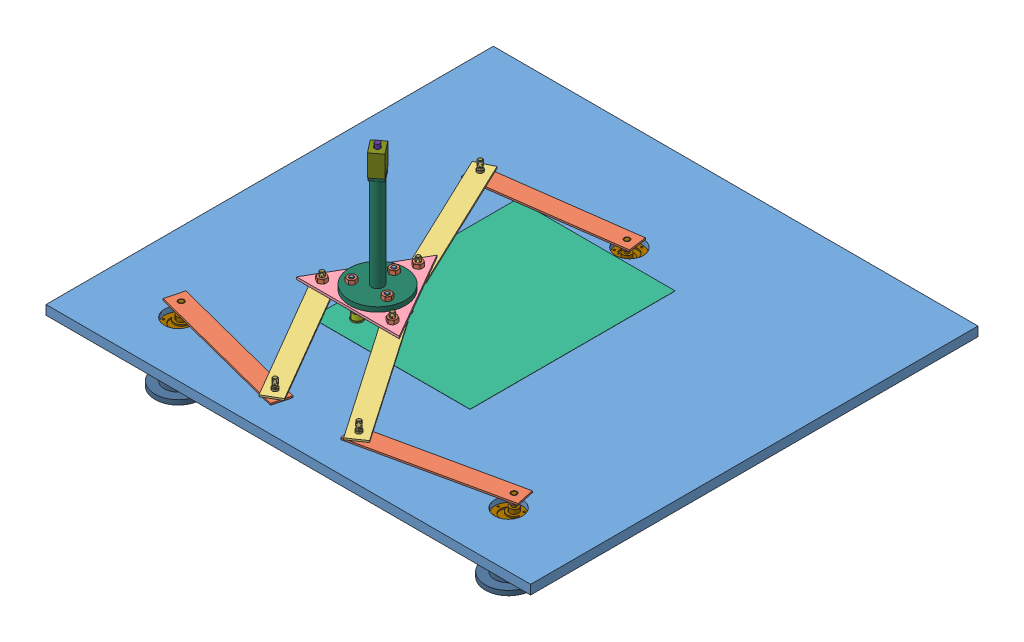
SolidWorks assembly 10_Full_3R_Assembly_rev2, configuration Default. Lengths in mm.
Overall size (660.4 280.02 609.6).
57 component instances, 20 part files, 127 mates.
Components (placement in the parent):
- 01_Base_Plate-1: 01_Base_Plate [Default] at (-311.7855 -6.35 287.7555) size (660.4 12.7 609.6)
- 02_A_Link-1: 02_A_Link [Default] at (-224.6047 18.389 215.2577) x (0.96847 0 0.24913) z (-0.24913 0 0.96847) size (203.2 2.29 25.4)
- 03_B_Link-1: 03_B_Link [Default] at (-19.5777 22.6594 254.9869) x (-0.503939 0 -0.863739) z (0.863739 0 -0.503939) size (203.2 2.29 25.4)
- 02_A_Link-2: 02_A_Link [Default] at (60.5102 18.389 258.3952) x (0.977346 0 -0.211648) z (0.211648 0 0.977346) size (203.2 2.29 25.4)
- 03_B_Link-2: 03_B_Link [Default] at (-48.2499 22.6594 93.5854) x (0.567054 0 0.823681) z (-0.823681 0 0.567054) size (203.2 2.29 25.4)
- 02_A_Link-3: 02_A_Link [Default] at (35.7031 20.675 -159.8663) x (-0.990962 0 0.134142) z (0.134142 0 0.990962) size (203.2 2.29 25.4)
- 03_B_Link-3: 03_B_Link [Default] at (-61.6497 22.6594 19.7713) x (-0.428635 0 -0.903478) z (0.903478 0 -0.428635) size (203.2 2.29 25.4)
- 04_Platform-1: 04_Platform [Default] at (-148.5445 28.2998 109.5445) size (139.95 3.17 121.2)
- 05_Pen-1: 05_Pen [Default] at (-78.5675 21.9916 69.1433) x (-0.946712 0 0.32208) z (-0.32208 0 -0.946712) size (12.7 123.83 12.7)
- 06_Paper-1: 06_Paper [Default] at (-114.9356 6.35 122.6553) size (215.9 0.25 279.4)
- 10_Ball_Transfer-1: 10_Ball_Transfer [Default] at (-74.2175 16.4553 44.1393) x (0.999999 0 0.001404) z (0.001404 0 -0.999999) size (14.51 13.76 14.51)
  - 09_Ball_Holder-1: 09_Ball_Holder [Default] at (19.6556 -3.653 -11.1258) size (14.51 9.53 14.51)
  - 08_Ball-1: 08_Ball [Default] at (19.6556 5.872 -11.1258) size (8.47 8.47 8.47)
- 10_Ball_Transfer-2: 10_Ball_Transfer [Default] at (-55.9862 16.4553 97.3042) x (-0.880102 0 0.474784) z (0.474784 0 0.880102) size (14.51 13.76 14.51)
  - 09_Ball_Holder-1: 09_Ball_Holder [Default] at (19.6556 -3.653 -11.1258) size (14.51 9.53 14.51)
  - 08_Ball-1: 08_Ball [Default] at (19.6556 5.872 -11.1258) size (8.47 8.47 8.47)
- 10_Ball_Transfer-3: 10_Ball_Transfer [Default] at (-121.7816 16.7093 43.4369) x (0.999295 0 0.037538) z (0.037538 0 -0.999295) size (14.51 13.76 14.51)
  - 09_Ball_Holder-1: 09_Ball_Holder [Default] at (19.6556 -3.653 -11.1258) size (14.51 9.53 14.51)
  - 08_Ball-1: 08_Ball [Default] at (19.6556 5.872 -11.1258) size (8.47 8.47 8.47)
- 07_Motor_rev2-1: 07_Motor_rev2 [Default] at (18.4145 -68.025 -177.0726) x (0 -1 0) z (-0.903522 0 0.428541) size (88.7 37 37)
- 07_Motor_rev2-2: 07_Motor_rev2 [Default] at (-206.5855 -68.025 212.6388) x (0 -1 0) z (0.93097 0 -0.365097) size (88.7 37 37)
- 07_Motor_rev2-3: 07_Motor_rev2 [Default] at (243.4145 -68.025 212.6388) x (0 -1 0) z (0.996416 0 0.084589) size (88.7 37 37)
- Motor_Mount-1: Motor_Mount [Default] at (18.4145 -74.93 -177.0726) x (-0.784855 0 0.61968) z (-0.61968 0 -0.784855) size (63.5 68.58 63.5)
- Motor_Mount-2: Motor_Mount [Default] at (243.4145 -74.93 212.6388) x (-0.847054 0 0.531507) z (-0.531507 0 -0.847054) size (63.5 68.58 63.5)
- Motor_Mount-3: Motor_Mount [Default] at (-206.5855 -74.93 212.6388) x (0.970749 0 0.240096) z (-0.240096 0 0.970749) size (63.5 68.58 63.5)
- 5909K24_Needle-Roller Thrust Bearing-1: 5909K24_Needle-Roller Thrust Bearing [5909K24] at (-154.7787 21.6672 -146.8976) x (-0.973754 0 -0.227604) z (0.227604 0 -0.973754) size (19.05 1.98 19.05)
- 91259A576_Alloy Steel Shoulder Screw-1: 91259A576_Alloy Steel Shoulder Screw [91259A576] at (-154.7787 12.8328 -146.8976) x (0.154475 0 0.987997) z (0 -1 0) size (11.11 11.11 26.95)
- 5909K24_Needle-Roller Thrust Bearing-3: 5909K24_Needle-Roller Thrust Bearing [5909K24] at (-36.9472 21.6672 250.4174) x (0.944791 0 0.327673) z (-0.327673 0 0.944791) size (19.05 1.98 19.05)
- 5909K24_Needle-Roller Thrust Bearing-4: 5909K24_Needle-Roller Thrust Bearing [5909K24] at (70.2346 21.6672 243.295) x (0.999962 0 -0.008701) z (0.008701 0 0.999962) size (19.05 1.98 19.05)
- 91259A576_Alloy Steel Shoulder Screw-2: 91259A576_Alloy Steel Shoulder Screw [91259A576] at (-36.9472 12.8328 250.4174) x (0.890655 0 -0.45468) z (0 -1 0) size (11.11 11.11 26.95)
- 91259A576_Alloy Steel Shoulder Screw-3: 91259A576_Alloy Steel Shoulder Screw [91259A576] at (70.2346 12.8328 243.295) x (0.621536 0 -0.783386) z (0 -1 0) size (11.11 11.11 26.95)
- 91259A576_Alloy Steel Shoulder Screw-4: 91259A576_Alloy Steel Shoulder Screw [91259A576] at (-126.5475 17.1031 96.8445) x (-0.287715 0 -0.957716) z (0 -1 0) size (11.11 11.11 26.95)
- 91259A576_Alloy Steel Shoulder Screw-5: 91259A576_Alloy Steel Shoulder Screw [91259A576] at (-30.5876 17.1031 96.8445) x (0.554326 0 -0.8323) z (0 -1 0) size (11.11 11.11 26.95)
- 91259A576_Alloy Steel Shoulder Screw-6: 91259A576_Alloy Steel Shoulder Screw [91259A576] at (-78.5675 17.1031 13.7408) x (0.999981 0 0.006147) z (0 -1 0) size (11.11 11.11 26.95)
- 5909K24_Needle-Roller Thrust Bearing-5: 5909K24_Needle-Roller Thrust Bearing [5909K24] at (-126.5475 25.9376 96.8445) x (0.999001 0 0.044697) z (-0.044697 0 0.999001) size (19.05 1.98 19.05)
- 5909K24_Needle-Roller Thrust Bearing-6: 5909K24_Needle-Roller Thrust Bearing [5909K24] at (-78.5675 25.9376 13.7408) x (0.99923 0 -0.03923) z (0.03923 0 0.99923) size (19.05 1.98 19.05)
- 5909K24_Needle-Roller Thrust Bearing-7: 5909K24_Needle-Roller Thrust Bearing [5909K24] at (-30.5876 25.9376 96.8445) x (0.999895 0 -0.014505) z (0.014505 0 0.999895) size (19.05 1.98 19.05)
- 6056N14_Carbon Steel Set Screw Collar-1: 6056N14_Carbon Steel Set Screw Collar [6056N14] at (-209.1411 14.389 206.122) x (0.989994 0 0.14111) z (0 1 0) size (12 12.47 8)
- 6056N14_Carbon Steel Set Screw Collar-2: 6056N14_Carbon Steel Set Screw Collar [6056N14] at (21.4143 14.389 -170.7479) x (0.948137 0 -0.317863) z (0 1 0) size (12 12.47 8)
- 6056N14_Carbon Steel Set Screw Collar-3: 6056N14_Carbon Steel Set Screw Collar [6056N14] at (244.0067 14.389 205.6639) x (0.994257 0 -0.107019) z (0 -1 0) size (12 12.47 8)
- 92510A763_Aluminum Unthreaded Spacer-1: 92510A763_Aluminum Unthreaded Spacer [92510A763] at (-102.5575 24.3311 55.2927) x (1 0 0) z (0 -1 0) size (12.7 12.7 7.94)
- 92510A763_Aluminum Unthreaded Spacer-2: 92510A763_Aluminum Unthreaded Spacer [92510A763] at (-78.5675 24.0771 96.8445) x (1 0 0) z (0 -1 0) size (12.7 12.7 7.94)
- 92510A763_Aluminum Unthreaded Spacer-3: 92510A763_Aluminum Unthreaded Spacer [92510A763] at (-54.5775 24.0771 55.2927) x (1 0 0) z (0 -1 0) size (12.7 12.7 7.94)
- PenHolder-1: PenHolder [Default] at (-78.5675 31.4748 69.1433) x (-0.790504 0 0.612456) z (-0.612456 0 -0.790504) size (76.2 138.35 76.2)
- SolenoidAssembly-1: SolenoidAssembly [Default] at (-45.0686 152.9554 87.7845) x (-0.790504 0 0.612456) z (-0.612456 0 -0.790504) size (17 55.9 22)
  - Solenoid_Mount-2: Solenoid_Mount [Default] at (6.5641 46.5695 46.2525) x (1 0 0) z (0 0 -1) size (17 29.7 22)
  - Solenoid_Shaft-1: Solenoid_Shaft [Default] at (15.0641 0.2373 35.2525) x (-0.773677 0 0.63358) z (-0.63358 0 -0.773677) size (6.9 51.9 6.9)
  - Solenoid_Cap-1: Solenoid_Cap [Default] at (15.0641 -3.7627 35.2525) x (0.200587 0 -0.979676) z (0.979676 0 0.200587) size (5 12 5)
- 90604A539_Pan Head Combination Phillips Slotted Screws-1: 90604A539_Pan Head Combination Phillips Slotted Screws [90604A539] at (-81.4936 44.1748 43.9124) x (-0.886591 0 -0.462554) z (0 -1 0) size (12.5 12.5 20.66)
- 90604A539_Pan Head Combination Phillips Slotted Screws-2: 90604A539_Pan Head Combination Phillips Slotted Screws [90604A539] at (-98.955 44.1748 84.2928) x (0.746863 0 0.664978) z (0 -1 0) size (12.5 12.5 20.66)
- 90604A539_Pan Head Combination Phillips Slotted Screws-3: 90604A539_Pan Head Combination Phillips Slotted Screws [90604A539] at (-55.2539 44.1748 79.2246) x (1 0 0) z (0 -1 0) size (12.5 12.5 20.66)
- 95462A029_Medium-Strength Steel Hex Nut-1: 95462A029_Medium-Strength Steel Hex Nut [95462A029] at (-55.2539 40.603 79.2246) x (-0.837169 0 -0.546944) z (0 -1 0) size (11.11 12.83 6.51)
- 95462A029_Medium-Strength Steel Hex Nut-2: 95462A029_Medium-Strength Steel Hex Nut [95462A029] at (-30.5876 34.253 96.8445) x (-1 0 0) z (0 1 0) size (11.11 12.83 6.51)
- 95462A029_Medium-Strength Steel Hex Nut-3: 95462A029_Medium-Strength Steel Hex Nut [95462A029] at (-81.4936 40.603 43.9124) x (-1 0 0) z (0 1 0) size (11.11 12.83 6.51)
- 95462A029_Medium-Strength Steel Hex Nut-4: 95462A029_Medium-Strength Steel Hex Nut [95462A029] at (-126.5475 34.253 96.8445) x (-1 0 0) z (0 1 0) size (11.11 12.83 6.51)
- 95462A029_Medium-Strength Steel Hex Nut-5: 95462A029_Medium-Strength Steel Hex Nut [95462A029] at (-78.5675 34.253 13.7408) x (-1 0 0) z (0 1 0) size (11.11 12.83 6.51)
- 95462A029_Medium-Strength Steel Hex Nut-6: 95462A029_Medium-Strength Steel Hex Nut [95462A029] at (-98.955 40.603 84.2928) x (-0.226701 0 0.973964) z (0 -1 0) size (11.11 12.83 6.51)
Mates (geometry in assembly coordinates):
- Concentric4: concentric anti-aligned: circle of 04_Platform-1; circle of 05_Pen-1
- Coincident21: coincident anti-aligned: plane of 01_Base_Plate-1 through (-311.7855 6.35 287.7555) normal (0 1 0); plane of 06_Paper-1 through (-114.9356 6.35 122.6553) normal (0 -1 0)
- Distance1: distance = 196.85 mm: line of 06_Paper-1 through (-114.9356 6.604 -156.7447) axis (0 0 1); line of 01_Base_Plate-1 through (-311.7855 6.35 -321.8445) axis (0 0 1)
- Distance2: distance = 165.1 mm: line of 06_Paper-1 through (100.9644 6.604 -156.7447) axis (-1 0 0); line of 01_Base_Plate-1 through (348.6145 6.35 -321.8445) axis (-1 0 0)
- Tangent1: tangent anti-aligned: plane of 06_Paper-1 through (-114.9356 6.604 122.6553) normal (0 1 0); sphere of 08_Roller-1
- Tangent2: tangent anti-aligned: plane of 06_Paper-1 through (-114.9356 6.604 122.6553) normal (0 1 0); sphere of 08_Roller-2
- Tangent3: tangent anti-aligned: plane of 06_Paper-1 through (-114.9356 6.604 122.6553) normal (0 1 0); sphere of 08_Roller-3
- Tangent4: tangent anti-aligned: plane of 04_Platform-1 through (-148.5445 28.2998 109.5445) normal (0 -1 0); sphere of 08_Roller-1
- Coincident37: coincident anti-aligned: plane of 02_A_Link-3 through (35.7031 18.389 -159.8663) normal (0 -1 0); plane of 07_Motor-3 through (15.6523 48.5738 -175.9022) normal (0 1 0)
- Concentric8: concentric aligned: circle of 02_A_Link-3; circle of 07_Motor-3
- Parallel3: parallel aligned: plane of 01_Base_Plate-1 through (-311.7855 6.35 287.7555) normal (0 0 1); plane of 04_Platform-1 through (-148.5445 31.4748 109.5445) normal (0 0 1)
- Concentric10: concentric anti-aligned: circle of 04_Platform-1; circle of 10_Ball_Transfer-1/09_Ball_Holder-1
- Concentric11: concentric anti-aligned: circle of 04_Platform-1; circle of 10_Ball_Transfer-3/09_Ball_Holder-1
- Concentric12: concentric anti-aligned: circle of 04_Platform-1; circle of 10_Ball_Transfer-2/09_Ball_Holder-1
- Concentric18: concentric aligned: circle of 01_Base_Plate-1; circle of 07_Motor_rev2-3
- Concentric20: concentric aligned: circle of 01_Base_Plate-1; circle of 07_Motor_rev2-2
- Concentric21: concentric aligned: circle of 01_Base_Plate-1; circle of 07_Motor_rev2-1
- Concentric23: concentric anti-aligned: circle of 02_A_Link-1; circle of 07_Motor_rev2-2
- Coincident45: coincident aligned: plane of 02_A_Link-1 through (-224.6047 20.675 215.2577) normal (0 1 0); plane of 07_Motor_rev2-2 through (-210.2364 20.675 203.3291) normal (0 1 0)
- Concentric24: concentric anti-aligned: circle of 02_A_Link-2; circle of 07_Motor_rev2-3
- Coincident46: coincident aligned: plane of 02_A_Link-2 through (60.5102 20.675 258.3952) normal (0 1 0); plane of 07_Motor_rev2-3 through (244.2604 20.675 202.6747) normal (0 1 0)
- Concentric25: concentric aligned: circle of 02_A_Link-3; circle of 07_Motor_rev2-1
- Coincident47: coincident aligned: plane of 02_A_Link-3 through (35.7031 20.675 -159.8663) normal (0 1 0); plane of 07_Motor_rev2-1 through (22.7 20.675 -168.0374) normal (0 1 0)
- Tangent5: tangent anti-aligned: plane of 01_Base_Plate-1 through (-311.7855 6.35 287.7555) normal (0 1 0); sphere of 10_Ball_Transfer-1/08_Ball-1
- Coincident51: coincident anti-aligned: plane of 01_Base_Plate-1 through (-311.7855 -6.35 287.7555) normal (0 -1 0); plane of Motor_Mount-1 through (2.2171 -6.35 -164.284) normal (0 1 0)
- Concentric26: concentric anti-aligned: cylinder of 07_Motor_rev2-1 through (18.4145 12.0864 -177.0726) axis (0 1 0) radius 18.5; cylinder of Motor_Mount-1 through (18.4145 -100.9975 -177.0726) axis (0 -1 0) radius 20.6375
- Concentric27: concentric anti-aligned: cylinder of 07_Motor_rev2-3 through (243.4145 12.0864 212.6388) axis (0 1 0) radius 18.5; cylinder of Motor_Mount-2 through (243.4145 -100.9975 212.6388) axis (0 -1 0) radius 19.05
- Coincident52: coincident anti-aligned: plane of 01_Base_Plate-1 through (-311.7855 -6.35 287.7555) normal (0 -1 0); plane of Motor_Mount-2 through (225.9335 -6.35 223.6078) normal (0 1 0)
- Coincident53: coincident anti-aligned: plane of 01_Base_Plate-1 through (-311.7855 -6.35 287.7555) normal (0 -1 0); plane of Motor_Mount-3 through (-186.5516 -6.35 217.5938) normal (0 1 0)
- Concentric29: concentric aligned: cylinder of 03_B_Link-3 through (-154.7787 22.6594 -146.8976) axis (0 1 0) radius 3.9688; cylinder of 91259A427_Alloy Steel Shoulder Screw-1 through (-164.7374 27.7812 -154.398) axis (0 1 0) radius 3.9688
- Concentric30: concentric aligned: cylinder of 02_A_Link-3 through (-154.7787 20.675 -146.8976) axis (0 -1 0) radius 3.9688; cylinder of 5909K24_Needle-Roller Thrust Bearing-1 through (-154.7787 20.675 -146.8976) axis (0 -1 0) radius 3.9624
- Tangent7: tangent anti-aligned: plane of 02_A_Link-3 through (35.7031 20.675 -159.8663) normal (0 1 0); cylinder of 5909K24_Needle-Roller Thrust Bearing-1 through (-148.3393 21.6672 -140.8598) axis (0.729494 0 0.683987) radius 0.9922
- Coincident58: coincident anti-aligned: plane of 07_Motor_rev2-1 through (25.8069 -22.225 -161.4868) normal (0 -1 0); plane of Motor_Mount-1 through (3.4631 -22.225 -165.2677) normal (0 1 0)
- Concentric31: concentric anti-aligned: cylinder of 07_Motor_rev2-2 through (-206.5855 12.0864 212.6388) axis (0 1 0) radius 18.5; cylinder of Motor_Mount-3 through (-206.5855 -100.9975 212.6388) axis (0 -1 0) radius 19.05
- Coincident61: coincident anti-aligned: plane of 01_Base_Plate-1 through (-311.7855 6.35 287.7555) normal (0 1 0); plane of 91259A427_Alloy Steel Shoulder Screw-1 through (-164.7374 6.35 -154.398) normal (0 -1 0)
- Concentric32: concentric anti-aligned: cylinder of 02_A_Link-3 through (-154.7787 20.675 -146.8976) axis (0 -1 0) radius 3.9688; cylinder of 03_B_Link-3 through (-154.7787 22.6594 -146.8976) axis (0 1 0) radius 3.9688
- Concentric33: concentric anti-aligned: circle of 03_B_Link-3; circle of 5909K24_Needle-Roller Thrust Bearing-2
- Tangent10: tangent anti-aligned: plane of 5909K24_Needle-Roller Thrust Bearing-1 through (-152.6108 22.1633 -156.1726) normal (0 1 0); cylinder of 5909K24_Needle-Roller Thrust Bearing-2 through (-163.8488 16.8055 -163.1804) axis (0.100661 0 -0.994921) radius 0.9922
- Coincident62: coincident anti-aligned: plane of 01_Base_Plate-1 through (-311.7855 6.35 287.7555) normal (0 1 0); plane of 91259A175_Alloy Steel Shoulder Screw-1 through (-164.7374 6.35 -154.398) normal (0 -1 0)
- Concentric34: concentric aligned: circle of 03_B_Link-3; circle of 91259A175_Alloy Steel Shoulder Screw-1
- Concentric36: concentric aligned: circle of 03_B_Link-3; circle of 91259A576_Alloy Steel Shoulder Screw-1
- Concentric37: concentric aligned: circle of 02_A_Link-2; circle of 03_B_Link-2
- Concentric38: concentric aligned: circle of 02_A_Link-1; circle of 03_B_Link-1
- Concentric39: concentric anti-aligned: cylinder of 02_A_Link-2 through (70.2346 18.389 243.295) axis (0 1 0) radius 3.9688; cylinder of 5909K24_Needle-Roller Thrust Bearing-4 through (70.2346 20.675 243.295) axis (0 -1 0) radius 3.9624
- Tangent13: tangent anti-aligned: plane of 02_A_Link-2 through (60.5102 20.675 258.3952) normal (0 1 0); cylinder of 5909K24_Needle-Roller Thrust Bearing-4 through (66.7145 21.6672 251.3901) axis (-0.398772 0 0.91705) radius 0.9922
- Coincident68: coincident anti-aligned: plane of 07_Motor_rev2-3 through (244.8737 -22.225 195.4507) normal (0 -1 0); plane of Motor_Mount-2 through (227.2782 -22.225 222.764) normal (0 1 0)
- Concentric43: concentric anti-aligned: cylinder of 03_B_Link-1 through (-36.9472 22.6594 250.4174) axis (0 1 0) radius 3.9688; cylinder of 5909K24_Needle-Roller Thrust Bearing-3 through (-36.9472 20.675 250.4174) axis (0 -1 0) radius 3.9624
- Coincident69: coincident anti-aligned: plane of 07_Motor_rev2-2 through (-212.8834 -22.225 196.5796) normal (0 -1 0); plane of Motor_Mount-3 through (-188.0927 -22.225 217.2127) normal (0 1 0)
- Tangent15: tangent anti-aligned: plane of 02_A_Link-1 through (-224.6047 20.675 215.2577) normal (0 1 0); cylinder of 5909K24_Needle-Roller Thrust Bearing-3 through (-42.7236 21.6672 243.7425) axis (-0.654377 0 -0.756168) radius 0.9922
- Concentric44: concentric aligned: cylinder of 03_B_Link-2 through (70.2346 22.6594 243.295) axis (0 1 0) radius 3.9688; cylinder of 91259A576_Alloy Steel Shoulder Screw-3 through (70.2346 39.0265 243.295) axis (0 1 0) radius 3.9688
- Coincident71: coincident anti-aligned: plane of 02_A_Link-3 through (35.7031 18.389 -159.8663) normal (0 -1 0); plane of 91259A576_Alloy Steel Shoulder Screw-1 through (-149.2892 18.389 -147.7559) normal (0 1 0)
- Coincident72: coincident anti-aligned: plane of 02_A_Link-2 through (60.5102 18.389 258.3952) normal (0 -1 0); plane of 91259A576_Alloy Steel Shoulder Screw-3 through (65.8819 18.389 239.8416) normal (0 1 0)
- Coincident73: coincident anti-aligned: plane of 02_A_Link-1 through (-224.6047 18.389 215.2577) normal (0 -1 0); plane of 91259A576_Alloy Steel Shoulder Screw-2 through (-39.4735 18.389 245.4687) normal (0 1 0)
- Concentric45: concentric aligned: cylinder of 02_A_Link-1 through (-36.9472 18.389 250.4174) axis (0 1 0) radius 3.9688; cylinder of 91259A576_Alloy Steel Shoulder Screw-2 through (-36.9472 39.0265 250.4174) axis (0 1 0) radius 3.9688
- Concentric46: concentric aligned: cylinder of 07_Motor_rev2-2 through (-209.1411 -68.025 206.122) axis (0 -1 0) radius 3; cylinder of 98541A114_External Retaining Ring-1 through (-200.6826 18.389 208.8764) axis (0 -1 0) radius 2.8
- Coincident74: coincident anti-aligned: plane of 02_A_Link-1 through (-224.6047 18.389 215.2577) normal (0 -1 0); plane of 98541A114_External Retaining Ring-1 through (-200.6826 18.389 208.8764) normal (0 1 0)
- Concentric49: concentric anti-aligned: cylinder of 03_B_Link-2 through (-30.5876 22.6594 96.8445) axis (0 1 0) radius 3.9688; cylinder of 04_Platform-1 through (-30.5876 31.4748 96.8445) axis (0 -1 0) radius 3.9688
- Concentric50: concentric anti-aligned: cylinder of 03_B_Link-1 through (-126.5475 22.6594 96.8445) axis (0 1 0) radius 3.9688; cylinder of 04_Platform-1 through (-126.5475 31.4748 96.8445) axis (0 -1 0) radius 3.9688
- Concentric51: concentric anti-aligned: cylinder of 03_B_Link-3 through (-78.5675 22.6594 13.7408) axis (0 1 0) radius 3.9688; cylinder of 04_Platform-1 through (-78.5675 31.4748 13.7408) axis (0 -1 0) radius 3.9688
- Coincident77: coincident anti-aligned: plane of 10_Ball_Transfer-1/09_Ball_Holder-1 through (-54.5775 20.1083 55.2927) normal (0 1 0); plane of Spacer_Platform-1 through (19.8558 20.1083 18.7709) normal (0 -1 0)
- Concentric52: concentric anti-aligned: circle of 10_Ball_Transfer-1/09_Ball_Holder-1; circle of Spacer_Platform-1
- Coincident78: coincident anti-aligned: plane of 04_Platform-1 through (-148.5445 28.2998 109.5445) normal (0 -1 0); plane of Spacer_Platform-1 through (19.8558 28.0458 18.7709) normal (0 1 0)
- Tangent16: tangent anti-aligned: plane of 01_Base_Plate-1 through (-311.7855 6.35 287.7555) normal (0 1 0); sphere of 10_Ball_Transfer-2/08_Ball-1
- Coincident79: coincident anti-aligned: plane of 10_Ball_Transfer-2/09_Ball_Holder-1 through (-78.5675 20.1083 96.8445) normal (0 1 0); plane of Spacer_Platform-2 through (-4.1341 20.1083 60.3228) normal (0 -1 0)
- Concentric53: concentric anti-aligned: circle of 10_Ball_Transfer-2/09_Ball_Holder-1; circle of Spacer_Platform-2
- Concentric54: concentric anti-aligned: circle of 10_Ball_Transfer-3/09_Ball_Holder-1; circle of Spacer_Platform-3
- Coincident82: coincident anti-aligned: plane of 10_Ball_Transfer-3/09_Ball_Holder-1 through (-102.5575 20.3623 55.2927) normal (0 1 0); plane of Spacer_Platform-3 through (-28.1241 20.911 18.7709) normal (0 -1 0)
- Parallel4: parallel anti-aligned: plane of 03_B_Link-2 through (-48.2499 24.9454 93.5854) normal (0 1 0); plane of 04_Platform-1 through (-148.5445 28.2998 109.5445) normal (0 -1 0)
- Parallel5: parallel aligned: plane of 03_B_Link-1 through (-19.5777 24.9454 254.9869) normal (0 1 0); plane of 04_Platform-1 through (-148.5445 31.4748 109.5445) normal (0 1 0)
- Parallel6: parallel aligned: plane of 03_B_Link-3 through (-61.6497 24.9454 19.7713) normal (0 1 0); plane of 04_Platform-1 through (-148.5445 31.4748 109.5445) normal (0 1 0)
- Tangent17: tangent anti-aligned: plane of 03_B_Link-2 through (-48.2499 22.6594 93.5854) normal (0 -1 0); cylinder of 5909K24_Needle-Roller Thrust Bearing-4 through (78.6532 21.6672 245.9496) axis (0.953709 0 0.30073) radius 0.9922
- Tangent18: tangent anti-aligned: plane of 03_B_Link-3 through (-61.6497 22.6594 19.7713) normal (0 -1 0); cylinder of 5909K24_Needle-Roller Thrust Bearing-1 through (-145.983 21.6672 -147.643) axis (0.996428 0 -0.084443) radius 0.9922
- Tangent19: tangent anti-aligned: plane of 03_B_Link-1 through (-19.5777 22.6594 254.9869) normal (0 -1 0); cylinder of 5909K24_Needle-Roller Thrust Bearing-3 through (-29.705 21.6672 245.3704) axis (0.820427 0 -0.571751) radius 0.9922
- Coincident85: coincident anti-aligned: plane of 03_B_Link-1 through (-19.5777 22.6594 254.9869) normal (0 -1 0); plane of 91259A576_Alloy Steel Shoulder Screw-4 through (-131.8688 22.6594 98.4432) normal (0 1 0)
- Concentric55: concentric aligned: cylinder of 03_B_Link-1 through (-126.5475 22.6594 96.8445) axis (0 1 0) radius 3.9688; cylinder of 91259A576_Alloy Steel Shoulder Screw-4 through (-126.5475 43.2969 96.8445) axis (0 1 0) radius 3.9688
- Concentric56: concentric anti-aligned: cylinder of 91259A576_Alloy Steel Shoulder Screw-4 through (-126.5475 43.2969 96.8445) axis (0 1 0) radius 3.9688; cylinder of 5909K24_Needle-Roller Thrust Bearing-5 through (-126.5475 24.9454 96.8445) axis (0 -1 0) radius 3.9624
- Tangent20: tangent anti-aligned: plane of 03_B_Link-1 through (-19.5777 24.9454 254.9869) normal (0 1 0); cylinder of 5909K24_Needle-Roller Thrust Bearing-5 through (-133.3649 25.9376 102.452) axis (-0.77231 0 0.635246) radius 0.9922
- Concentric57: concentric anti-aligned: cylinder of 04_Platform-1 through (-30.5876 31.4748 96.8445) axis (0 -1 0) radius 3.9688; cylinder of 91259A576_Alloy Steel Shoulder Screw-5 through (-30.5876 43.2969 96.8445) axis (0 1 0) radius 3.9688
- Coincident86: coincident anti-aligned: plane of 03_B_Link-2 through (-48.2499 22.6594 93.5854) normal (0 -1 0); plane of 91259A576_Alloy Steel Shoulder Screw-5 through (-35.212 22.6594 93.7646) normal (0 1 0)
- Concentric58: concentric anti-aligned: cylinder of 04_Platform-1 through (-78.5675 31.4748 13.7408) axis (0 -1 0) radius 3.9688; cylinder of 91259A576_Alloy Steel Shoulder Screw-6 through (-78.5675 43.2969 13.7408) axis (0 1 0) radius 3.9688
- Concentric59: concentric anti-aligned: cylinder of 91259A576_Alloy Steel Shoulder Screw-5 through (-30.5876 43.2969 96.8445) axis (0 1 0) radius 3.9688; cylinder of 5909K24_Needle-Roller Thrust Bearing-7 through (-30.5876 24.9454 96.8445) axis (0 -1 0) radius 3.9624
- Tangent24: tangent anti-aligned: plane of 03_B_Link-2 through (-48.2499 24.9454 93.5854) normal (0 1 0); cylinder of 5909K24_Needle-Roller Thrust Bearing-7 through (-30.4595 25.9376 105.6709) axis (0.014505 0 0.999895) radius 0.9922
- Concentric60: concentric anti-aligned: cylinder of 91259A576_Alloy Steel Shoulder Screw-6 through (-78.5675 43.2969 13.7408) axis (0 1 0) radius 3.9688; cylinder of 5909K24_Needle-Roller Thrust Bearing-6 through (-78.5675 24.9454 13.7408) axis (0 -1 0) radius 3.9624
- Tangent25: tangent anti-aligned: plane of 03_B_Link-3 through (-61.6497 24.9454 19.7713) normal (0 1 0); cylinder of 5909K24_Needle-Roller Thrust Bearing-6 through (-69.8315 25.9376 12.4744) axis (0.989656 0 -0.143463) radius 0.9922
- Coincident88: coincident anti-aligned: plane of 03_B_Link-3 through (-61.6497 22.6594 19.7713) normal (0 -1 0); plane of 91259A576_Alloy Steel Shoulder Screw-6 through (-78.5334 22.6594 8.1847) normal (0 1 0)
- Concentric61: concentric anti-aligned: cylinder of 07_Motor_rev2-1 through (21.4143 -68.025 -170.7479) axis (0 -1 0) radius 3; cylinder of grainger-2alx5-1 through (24.5848 9.389 -180.3783) axis (0 1 0) radius 1.5
- Coincident89: coincident anti-aligned: plane of 02_A_Link-3 through (35.7031 18.389 -159.8663) normal (0 -1 0); plane of grainger-2alx5-1 through (24.5848 18.389 -180.3783) normal (0 1 0)
- Concentric62: concentric anti-aligned: cylinder of 07_Motor_rev2-3 through (244.0067 -68.025 205.6639) axis (0 -1 0) radius 3; cylinder of grainger-2alx5-2 through (238.4578 9.389 207.6961) axis (0 1 0) radius 1.5
- Coincident90: coincident anti-aligned: plane of 02_A_Link-2 through (60.5102 18.389 258.3952) normal (0 -1 0); plane of grainger-2alx5-2 through (238.4578 18.389 207.6961) normal (0 1 0)
- Concentric63: concentric anti-aligned: cylinder of 07_Motor_rev2-2 through (-209.1411 -68.025 206.122) axis (0 -1 0) radius 3; cylinder of grainger-2alx5-3 through (-199.783 9.389 210.9877) axis (0 1 0) radius 1.5
- Coincident91: coincident anti-aligned: plane of 02_A_Link-1 through (-224.6047 18.389 215.2577) normal (0 -1 0); plane of grainger-2alx5-3 through (-199.783 18.389 210.9877) normal (0 1 0)
- Concentric64: concentric aligned: cylinder of 07_Motor_rev2-2 through (-209.1411 -68.025 206.122) axis (0 -1 0) radius 3; cylinder of 6056N14_Carbon Steel Set Screw Collar-1 through (-209.1411 18.389 206.122) axis (0 -1 0) radius 3
- Coincident92: coincident anti-aligned: plane of 02_A_Link-1 through (-224.6047 18.389 215.2577) normal (0 -1 0); plane of 6056N14_Carbon Steel Set Screw Collar-1 through (-209.1411 18.389 206.122) normal (0 1 0)
- Concentric65: concentric anti-aligned: cylinder of 07_Motor_rev2-3 through (244.0067 -68.025 205.6639) axis (0 -1 0) radius 3; cylinder of 6056N14_Carbon Steel Set Screw Collar-3 through (244.0067 10.389 205.6639) axis (0 1 0) radius 3
- Coincident93: coincident anti-aligned: plane of 02_A_Link-2 through (60.5102 18.389 258.3952) normal (0 -1 0); plane of 6056N14_Carbon Steel Set Screw Collar-3 through (244.0067 18.389 205.6639) normal (0 1 0)
- Concentric66: concentric aligned: cylinder of 07_Motor_rev2-1 through (21.4143 -68.025 -170.7479) axis (0 -1 0) radius 3; cylinder of 6056N14_Carbon Steel Set Screw Collar-2 through (21.4143 18.389 -170.7479) axis (0 -1 0) radius 3
- Coincident94: coincident anti-aligned: plane of 02_A_Link-3 through (35.7031 18.389 -159.8663) normal (0 -1 0); plane of 6056N14_Carbon Steel Set Screw Collar-2 through (21.4143 18.389 -170.7479) normal (0 1 0)
- Coincident95: coincident anti-aligned: plane of 10_Ball_Transfer-3/09_Ball_Holder-1 through (-102.5575 20.3623 55.2927) normal (0 1 0); plane of 92510A763_Aluminum Unthreaded Spacer-1 through (-102.5575 20.3623 55.2927) normal (0 -1 0)
- Concentric67: concentric aligned: circle of 10_Ball_Transfer-3/09_Ball_Holder-1; circle of 92510A763_Aluminum Unthreaded Spacer-1
- Tangent26: tangent anti-aligned: plane of 06_Paper-1 through (-114.9356 6.604 122.6553) normal (0 1 0); sphere of 10_Ball_Transfer-3/08_Ball-1
- Coincident97: coincident anti-aligned: plane of 04_Platform-1 through (-148.5445 28.2998 109.5445) normal (0 -1 0); plane of 92510A763_Aluminum Unthreaded Spacer-1 through (-102.5575 28.2998 55.2927) normal (0 1 0)
- Coincident98: coincident aligned: circle of 10_Ball_Transfer-2/09_Ball_Holder-1; circle of 92510A763_Aluminum Unthreaded Spacer-2
- Coincident99: coincident anti-aligned: plane of 10_Ball_Transfer-1/09_Ball_Holder-1 through (-54.5775 20.1083 55.2927) normal (0 1 0); plane of 92510A763_Aluminum Unthreaded Spacer-3 through (-54.5775 20.1083 55.2927) normal (0 -1 0)
- Coincident100: coincident aligned: circle of 10_Ball_Transfer-1/09_Ball_Holder-1; circle of 92510A763_Aluminum Unthreaded Spacer-3
- Concentric68: concentric aligned: cylinder of 05_Pen-1 through (-78.5675 21.9916 69.1433) axis (0 -1 0) radius 6.35; cylinder of PenHolder-1 through (-78.5675 185.0304 69.1433) axis (0 -1 0) radius 7.1437
- Coincident101: coincident anti-aligned: plane of 04_Platform-1 through (-148.5445 31.4748 109.5445) normal (0 1 0); plane of PenHolder-1 through (-78.5675 31.4748 69.1433) normal (0 -1 0)
- Concentric69: concentric aligned: cylinder of PenHolder-1 through (-78.5675 31.4748 69.1433) axis (0 1 0) radius 3; cylinder of SolenoidAssembly-1/Solenoid_Cap-1 through (-78.5675 269.9672 69.1433) axis (0 1 0) radius 2.5
- Coincident102: coincident anti-aligned: plane of PenHolder-1 through (-78.5675 169.8248 69.1433) normal (0 1 0); plane of SolenoidAssembly-1/Solenoid_Mount-2 through (-65.1112 169.8248 72.633) normal (0 -1 0)
- Concentric70: concentric anti-aligned: circle of PenHolder-1; circle of 90604A539_Pan Head Combination Phillips Slotted Screws-1
- Coincident103: coincident anti-aligned: plane of 04_Platform-1 through (-148.5445 28.2998 109.5445) normal (0 -1 0); plane of 90604A539_Pan Head Combination Phillips Slotted Screws-1 through (-84.0138 28.2998 48.7428) normal (0 1 0)
- Concentric71: concentric anti-aligned: circle of PenHolder-1; circle of 90604A539_Pan Head Combination Phillips Slotted Screws-2
- Coincident104: coincident anti-aligned: plane of 04_Platform-1 through (-148.5445 28.2998 109.5445) normal (0 -1 0); plane of 90604A539_Pan Head Combination Phillips Slotted Screws-2 through (-95.332 28.2998 80.2237) normal (0 1 0)
- Concentric72: concentric anti-aligned: circle of PenHolder-1; circle of 90604A539_Pan Head Combination Phillips Slotted Screws-3
- Coincident105: coincident anti-aligned: plane of 04_Platform-1 through (-148.5445 28.2998 109.5445) normal (0 -1 0); plane of 90604A539_Pan Head Combination Phillips Slotted Screws-3 through (-55.2539 28.2998 73.7763) normal (0 1 0)
- Coincident106: coincident anti-aligned: plane of PenHolder-1 through (-108.6857 37.8248 92.4779) normal (0 1 0); plane of 95462A029_Medium-Strength Steel Hex Nut-1 through (-48.8478 37.8248 79.5781) normal (0 -1 0)
- Concentric73: concentric anti-aligned: circle of 90604A539_Pan Head Combination Phillips Slotted Screws-3; circle of 95462A029_Medium-Strength Steel Hex Nut-1
- Concentric74: concentric aligned: circle of 90604A539_Pan Head Combination Phillips Slotted Screws-1; circle of 95462A029_Medium-Strength Steel Hex Nut-3
- Coincident109: coincident anti-aligned: plane of PenHolder-1 through (-108.6857 37.8248 92.4779) normal (0 1 0); plane of 95462A029_Medium-Strength Steel Hex Nut-3 through (-75.9374 37.8248 47.1203) normal (0 -1 0)
- Concentric75: concentric aligned: circle of 91259A576_Alloy Steel Shoulder Screw-5; circle of 95462A029_Medium-Strength Steel Hex Nut-2
- Coincident110: coincident anti-aligned: plane of 04_Platform-1 through (-148.5445 31.4748 109.5445) normal (0 1 0); plane of 95462A029_Medium-Strength Steel Hex Nut-2 through (-25.0313 31.4748 100.0524) normal (0 -1 0)
- Concentric76: concentric aligned: circle of 91259A576_Alloy Steel Shoulder Screw-4; circle of 95462A029_Medium-Strength Steel Hex Nut-4
- Coincident112: coincident anti-aligned: plane of 04_Platform-1 through (-148.5445 31.4748 109.5445) normal (0 1 0); plane of 95462A029_Medium-Strength Steel Hex Nut-4 through (-120.9912 31.4748 100.0524) normal (0 -1 0)
- Concentric77: concentric aligned: circle of 91259A576_Alloy Steel Shoulder Screw-6; circle of 95462A029_Medium-Strength Steel Hex Nut-5
- Coincident113: coincident anti-aligned: plane of 04_Platform-1 through (-148.5445 31.4748 109.5445) normal (0 1 0); plane of 95462A029_Medium-Strength Steel Hex Nut-5 through (-73.0113 31.4748 16.9487) normal (0 -1 0)
- Coincident114: coincident anti-aligned: plane of PenHolder-1 through (-108.6857 37.8248 92.4779) normal (0 1 0); plane of 95462A029_Medium-Strength Steel Hex Nut-6 through (-100.8198 37.8248 78.154) normal (0 -1 0)
- Concentric78: concentric anti-aligned: circle of 90604A539_Pan Head Combination Phillips Slotted Screws-2; circle of 95462A029_Medium-Strength Steel Hex Nut-6
- Parallel8: parallel aligned: line of PenHolder-1 through (-67.2548 169.8248 69.8662) axis (-0.612456 0 -0.790504); line of SolenoidAssembly-1/Solenoid_Mount-2 through (-65.1112 169.8248 72.633) axis (-0.612456 0 -0.790504)
